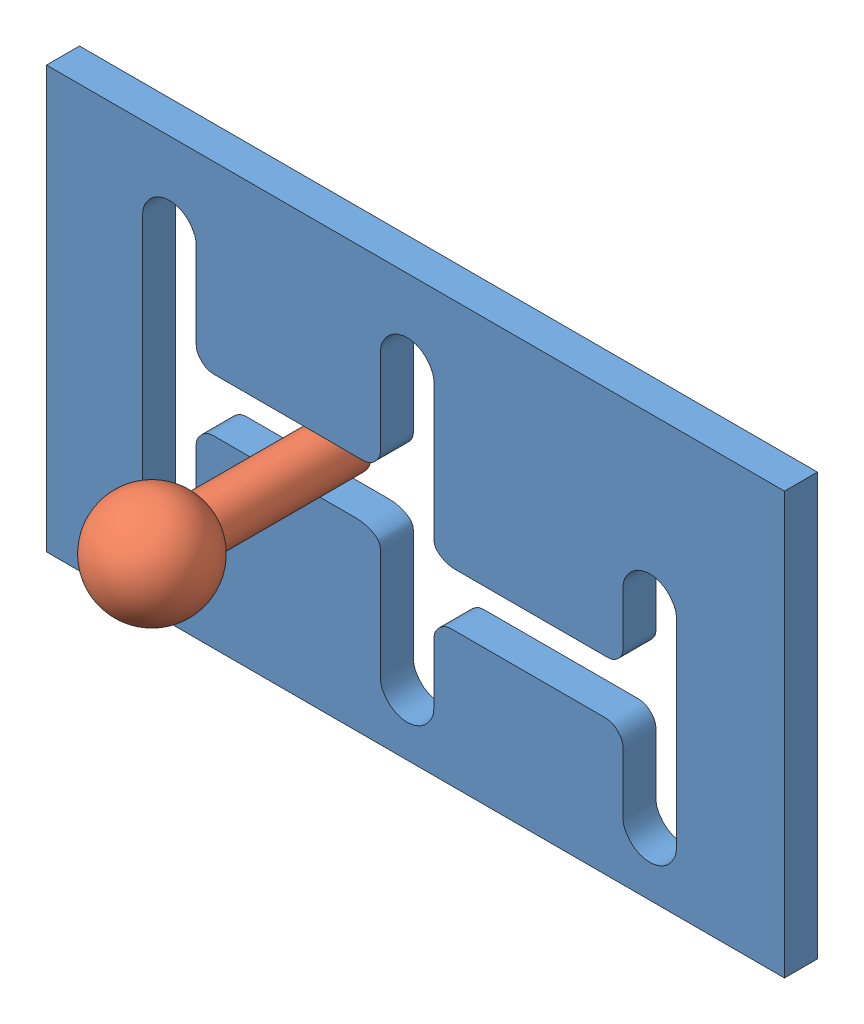
SolidWorks assembly rowek, configuration Domyślna. Lengths in mm.
Overall size (223.84 127.91 75).
2 component instances, 2 part files, 6 mates.
Components (placement in the parent):
- Część2^rowek-1: Część2^rowek [Domyślna] at origin size (223.84 127.91 10) (virtual)
- Część3^rowek-1: Część3^rowek [Domyślna] at (-3536.8862 -540.2916 80) x (-0.623883 -0.781518 0) z (0 0 1) size (31.87 31.88 75) (virtual)
Mates (geometry in assembly coordinates):
- Ustalone1: in place: plane of Część2^rowek-1 through (0 0 0) normal (0 0 1); moOrthogonalPlaneRef_w of Część2^rowek-1 through (0 0 0) normal (0 1 0); plane of Część2^rowek-1 through (0 0 0) normal (1 0 0); unknown of Część2^rowek-1
- Wspólnie1: coincident: plane of assembly; plane of Część2^rowek-1; plane of assembly
- Wspólnie2: coincident: plane of assembly; plane of Część2^rowek-1 through (0 0 0) normal (0 1 0); moOrthogonalPlaneRef_w of assembly
- Wspólnie3: coincident: plane of assembly; plane of Część2^rowek-1 through (0 0 0) normal (1 0 0); moOrthogonalPlaneRef_w of assembly
- Wspólnie4: coincident: plane of Część2^rowek-1 through (0 0 0) normal (0 0 -1); plane of ? through (-1.8515 39.0993 0) normal (0 0 -1)
- Wiązanie krzywki styczne1: cam tangent: face of Część2^rowek-1; cylinder of Część3^rowek-1 through (-1.8515 39.0993 45) axis (0 0 -1) radius 7.5
